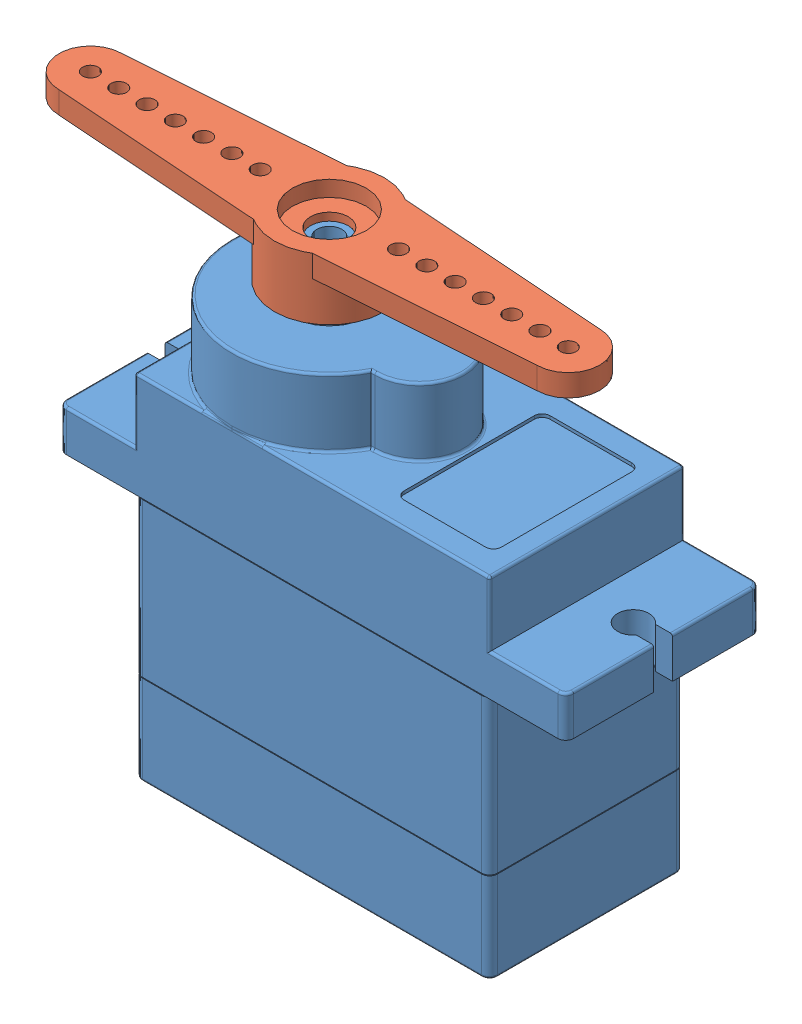
SolidWorks assembly microservoAssembly, configuration Default. Lengths in mm.
Overall size (38.45 31.3 12.5).
2 component instances, 2 part files, 2 mates.
Components (placement in the parent):
- microservoSG90-1: microservoSG90 [Default] at (7.8094 3.3655 26.0766) size (32.3 29.8 12.5)
- microservoArm-1: microservoArm [A2] at (2.7094 34.6655 26.0766) x (-1 0 0.000751) z (0.000751 0 1) size (34.4 3.9 7)
Mates (geometry in assembly coordinates):
- Concentric1: concentric: circle of microservoSG90-1; circle of microservoArm-1
- Coincident2: coincident: plane of microservoSG90-1 through (2.7094 33.1655 26.0766) normal (0 1 0); plane of microservoArm-1 through (2.7094 33.1655 26.0766) normal (0 -1 0)
